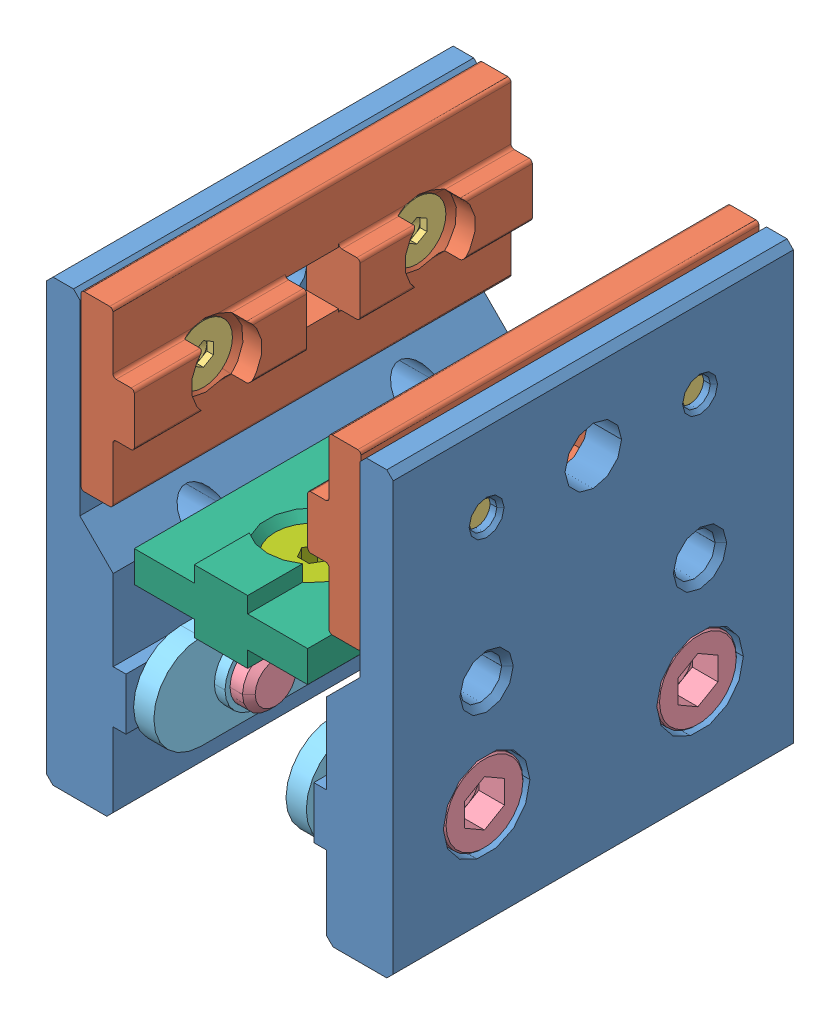
SolidWorks assembly 6730, configuration Default. Lengths in mm.
Overall size (43.42 52.6 47.9).
18 component instances, 8 part files, 0 mates.
Components (placement in the parent):
- _6760_p_4-1: _6760_p_4 [Default] at (-20.6248 -12.7 0) x (-1 0 0) z (0 0 -1) size (10.53 52.37 47.63)
- _6705_p_6-1: _6705_p_6 [Default] at (-16.6624 29.591 0) x (-1 0 0) z (0 0 -1) size (6.35 20.62 47.37)
- _8_32_1_8-1: _8_32_1_8 [Default] at (-14.1994 29.591 -12.7) x (0 0 1) z (0 -1 0) size (6.9 6.35 6.9)
- _8_32_1_8-2: _8_32_1_8 [Default] at (-14.1994 29.591 12.7) x (0 0 1) z (0 -1 0) size (6.9 6.35 6.9)
- _3058_11-1: _3058_11 [Default] at (-14.0208 0 -12.7) x (1 0 0) z (0 0 -1) size (15.88 9.53 9.53)
- _3280_13-1: _3280_13 [Default] at (-9.2075 0 -12.7) x (0 0 1) z (1 0 0) size (47.63 11.25 3.68)
- _3058_11-2: _3058_11 [Default] at (-14.0208 0 12.7) x (1 0 0) z (0 0 -1) size (15.88 9.53 9.53)
- _6760_p_4-2: _6760_p_4 [Default] at (20.6248 -12.7 0) size (10.53 52.37 47.63)
- _6705_p_6-2: _6705_p_6 [Default] at (16.6624 29.591 0) size (6.35 20.62 47.37)
- _8_32_1_8-3: _8_32_1_8 [Default] at (14.1994 29.591 12.7) x (0 0 -1) z (0 -1 0) size (6.9 6.35 6.9)
- _8_32_1_8-4: _8_32_1_8 [Default] at (14.1994 29.591 -12.7) x (0 0 -1) z (0 -1 0) size (6.9 6.35 6.9)
- _3058_11-3: _3058_11 [Default] at (14.0208 0 12.7) x (-1 0 0) z (0 0 1) size (15.88 9.53 9.53)
- _3280_13-2: _3280_13 [Default] at (9.2075 0 12.7) x (0 0 -1) z (-1 0 0) size (47.63 11.25 3.68)
- _3058_11-4: _3058_11 [Default] at (14.0208 0 -12.7) x (-1 0 0) z (0 0 1) size (15.88 9.53 9.53)
- _6792_p_23-1: _6792_p_23 [Default] at (0 14.5542 0) x (0 -1 0) z (0 0 1) size (7.52 20.62 47.37)
- _FHSCS_8_32_25-1: _FHSCS_8_32_25 [Default] at (0 12.663 12.7) x (0 0 -1) z (1 0 0) size (9.12 9.53 9.12)
- _3281_27-1: _3281_27 [Default] at (0 9.2837 12.7) x (0 0 -1) z (0 -1 0) size (34.93 11.25 3.18)
- _FHSCS_8_32_25-2: _FHSCS_8_32_25 [Default] at (0 12.663 -12.7) x (0 0 -1) z (1 0 0) size (9.12 9.53 9.12)
